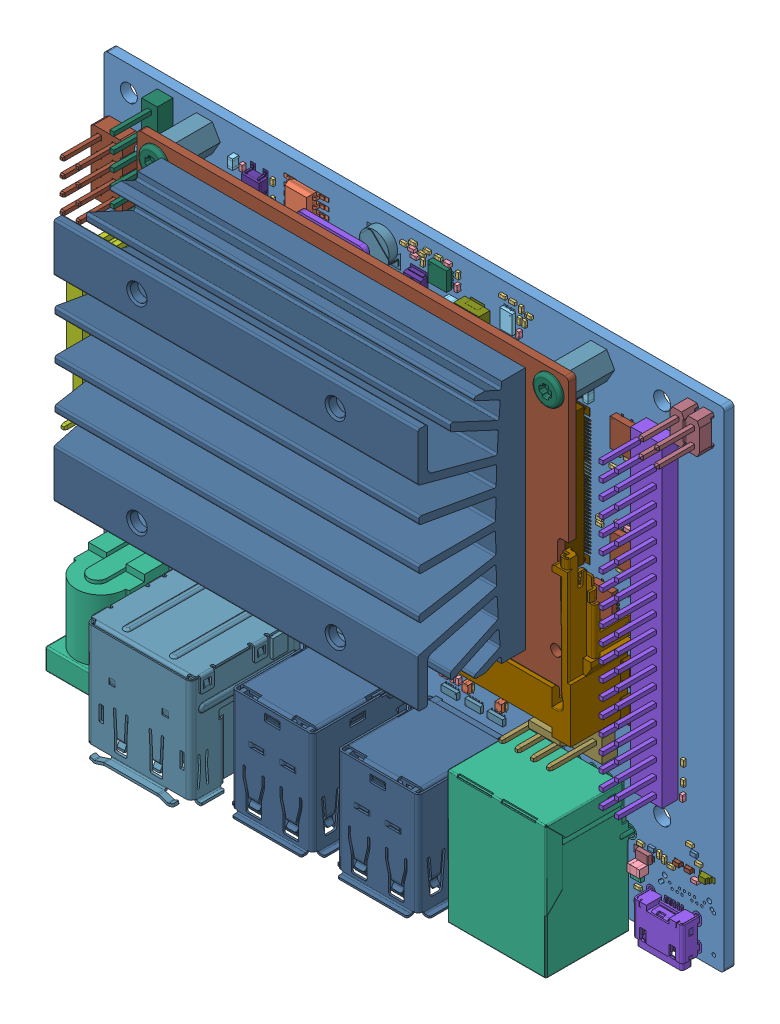
SolidWorks assembly Jetson nano_fixed.step, configuration Default. Lengths in mm.
Overall size (100 81.03 30.51).
400 component instances, 70 part files, 0 mates.
Components (placement in the parent):
- 142-13449-1000-A02_ASM.step-1: 142-13449-1000-A02_ASM.step [Default] at origin size (100 81.03 23.18)
  - 142-13449-1000-A02.step-1: 142-13449-1000-A02.step [Default] at origin size (100 79 1.57)
  - 315-1109-000_1.step-1: 315-1109-000_1.step [Default] at (5.6 4.9 1.575) x (-1 0 0) z (0 0 1) size (4.5 3.5 0.8)
  - 0402_H040.step-1: 0402_H040.step [Default] at (8 -0.825 1.575) size (1 0.5 0.4)
  - 0402_H060.step-1: 0402_H060.step [Default] at (1 5 1.575) x (0 -1 0) z (0 0 1) size (1 0.5 0.6)
  - 0402_H040.step-2: 0402_H040.step [Default] at (9.9 -0.3 1.575) size (1 0.5 0.4)
  - 0402_H040.step-3: 0402_H040.step [Default] at (8.296 51.194 1.575) x (-1 0 0) z (0 0 1) size (1 0.5 0.4)
  - 0402_H040.step-4: 0402_H040.step [Default] at (76.2 36.9 1.575) x (-1 0 0) z (0 0 1) size (1 0.5 0.4)
  - 0402_H040.step-5: 0402_H040.step [Default] at (37.8 2.87 1.575) x (0 -1 0) z (0 0 1) size (1 0.5 0.4)
  - 0402_H040.step-6: 0402_H040.step [Default] at (38.6 2.87 1.575) x (0 -1 0) z (0 0 1) size (1 0.5 0.4)
  - 0402_H060.step-2: 0402_H060.step [Default] at (14.2 7.7 1.575) x (0 -1 0) z (0 0 1) size (1 0.5 0.6)
  - 0402_H040.step-7: 0402_H040.step [Default] at (64 27.5 1.575) x (-1 0 0) z (0 0 1) size (1 0.5 0.4)
  - 0402_H060.step-3: 0402_H060.step [Default] at (18.6 43.15 1.575) x (-1 0 0) z (0 0 1) size (1 0.5 0.6)
  - 0402_H060.step-4: 0402_H060.step [Default] at (65.5 52.8 1.575) x (0 1 0) z (0 0 1) size (1 0.5 0.6)
  - 0402_H060.step-5: 0402_H060.step [Default] at (64 28.4 1.575) x (-1 0 0) z (0 0 1) size (1 0.5 0.6)
  - 0402_H040.step-8: 0402_H040.step [Default] at (60.95 25.85 1.575) size (1 0.5 0.4)
  - 0402_H060.step-6: 0402_H060.step [Default] at (17.3 7.7 1.575) x (0 -1 0) z (0 0 1) size (1 0.5 0.6)
  - 0402_H060.step-7: 0402_H060.step [Default] at (18.6 7.7 1.575) x (0 -1 0) z (0 0 1) size (1 0.5 0.6)
  - 0402_H060.step-8: 0402_H060.step [Default] at (12.9 7.7 1.575) x (0 -1 0) z (0 0 1) size (1 0.5 0.6)
  - 0402_H060.step-9: 0402_H060.step [Default] at (80.9 37.7 1.575) x (-1 0 0) z (0 0 1) size (1 0.5 0.6)
  - 0402_H040.step-9: 0402_H040.step [Default] at (79.5 31.3 1.575) size (1 0.5 0.4)
  - 0402_H040.step-10: 0402_H040.step [Default] at (81 31.3 1.575) x (-1 0 0) z (0 0 1) size (1 0.5 0.4)
  - 0402_H060.step-10: 0402_H060.step [Default] at (79.3 37.7 1.575) size (1 0.5 0.6)
  - 0402_H060.step-11: 0402_H060.step [Default] at (74.8 4.05 1.575) x (-1 0 0) z (0 0 1) size (1 0.5 0.6)
  - 0402_H040.step-11: 0402_H040.step [Default] at (65.675 6.15 1.575) x (0 -1 0) z (0 0 1) size (1 0.5 0.4)
  - 0402_H060.step-12: 0402_H060.step [Default] at (67.7 6.85 1.575) x (0 1 0) z (0 0 1) size (1 0.5 0.6)
  - 0402_H040.step-12: 0402_H040.step [Default] at (64.475 5.8 1.575) x (-1 0 0) z (0 0 1) size (1 0.5 0.4)
  - 0402_H040.step-13: 0402_H040.step [Default] at (67.725 5.325 1.575) x (0 1 0) z (0 0 1) size (1 0.5 0.4)
  - 0402_H060.step-13: 0402_H060.step [Default] at (46.1 59.45 1.575) size (1 0.5 0.6)
  - 0402_H040.step-14: 0402_H040.step [Default] at (44.65 59.45 1.575) size (1 0.5 0.4)
  - 0402_H040.step-15: 0402_H040.step [Default] at (46.1 60.25 1.575) size (1 0.5 0.4)
  - 0402_H060.step-14: 0402_H060.step [Default] at (53.35 57.7 1.575) x (0 -1 0) z (0 0 1) size (1 0.5 0.6)
  - 0402_H040.step-16: 0402_H040.step [Default] at (47.6 59.45 1.575) size (1 0.5 0.4)
  - 0402_H040.step-17: 0402_H040.step [Default] at (48.4 60.25 1.575) size (1 0.5 0.4)
  - 0402_H040.step-18: 0402_H040.step [Default] at (47.7 58.325 1.575) x (0 1 0) z (0 0 1) size (1 0.5 0.4)
  - 0402_H060.step-15: 0402_H060.step [Default] at (46.5 58.65 1.575) x (-1 0 0) z (0 0 1) size (1 0.5 0.6)
  - 0402_H060.step-16: 0402_H060.step [Default] at (51.8 60.25 1.575) size (1 0.5 0.6)
  - 0402_H040.step-19: 0402_H040.step [Default] at (53.35 59.4 1.575) x (0 -1 0) z (0 0 1) size (1 0.5 0.4)
  - 0402_H040.step-20: 0402_H040.step [Default] at (50.2 60.25 1.575) x (-1 0 0) z (0 0 1) size (1 0.5 0.4)
  - 0402_H060.step-17: 0402_H060.step [Default] at (18.6 43.95 1.575) x (-1 0 0) z (0 0 1) size (1 0.5 0.6)
  - 0402_H060.step-18: 0402_H060.step [Default] at (52.75 2.9 1.575) x (0 -1 0) z (0 0 1) size (1 0.5 0.6)
  - 0402_H060.step-19: 0402_H060.step [Default] at (22.35 47.4 1.575) x (-1 0 0) z (0 0 1) size (1 0.5 0.6)
  - 0402_H060.step-20: 0402_H060.step [Default] at (20.55 47.4 1.575) x (-1 0 0) z (0 0 1) size (1 0.5 0.6)
  - 0402_H060.step-21: 0402_H060.step [Default] at (21.95 34.55 1.575) x (0 -1 0) z (0 0 1) size (1 0.5 0.6)
  - 0402_H060.step-22: 0402_H060.step [Default] at (21.05 34.55 1.575) x (0 -1 0) z (0 0 1) size (1 0.5 0.6)
  - 0402_H060.step-23: 0402_H060.step [Default] at (53.55 2.9 1.575) x (0 -1 0) z (0 0 1) size (1 0.5 0.6)
  - 0402_H060.step-24: 0402_H060.step [Default] at (25.4 54 1.575) x (-1 0 0) z (0 0 1) size (1 0.5 0.6)
  - 0402_H060.step-25: 0402_H060.step [Default] at (24 34.58 1.575) x (0 -1 0) z (0 0 1) size (1 0.5 0.6)
  - 0402_H040.step-21: 0402_H040.step [Default] at (55.6 2.95 1.575) x (0 -1 0) z (0 0 1) size (1 0.5 0.4)
  - 0402_H040.step-22: 0402_H040.step [Default] at (20.13 34.53 1.575) x (0 1 0) z (0 0 1) size (1 0.5 0.4)
  - 0402_H060.step-26: 0402_H060.step [Default] at (18.4 35.15 1.575) x (0 1 0) z (0 0 1) size (1 0.5 0.6)
  - 0402_H060.step-27: 0402_H060.step [Default] at (18.4 36.75 1.575) x (0 1 0) z (0 0 1) size (1 0.5 0.6)
  - 0402_H040.step-23: 0402_H040.step [Default] at (39.6 2.87 1.575) x (0 -1 0) z (0 0 1) size (1 0.5 0.4)
  - 0402_H040.step-24: 0402_H040.step [Default] at (40.4 2.87 1.575) x (0 -1 0) z (0 0 1) size (1 0.5 0.4)
  - 0402_H040.step-25: 0402_H040.step [Default] at (60.95 2.95 1.575) x (0 -1 0) z (0 0 1) size (1 0.5 0.4)
  - 0402_H040.step-26: 0402_H040.step [Default] at (60.15 2.95 1.575) x (0 -1 0) z (0 0 1) size (1 0.5 0.4)
  - 0402_H040.step-27: 0402_H040.step [Default] at (54.8 2.95 1.575) x (0 -1 0) z (0 0 1) size (1 0.5 0.4)
  - 0402_H040.step-28: 0402_H040.step [Default] at (31.6 54 1.575) size (1 0.5 0.4)
  - 0402_H040.step-29: 0402_H040.step [Default] at (27.4 54 1.575) size (1 0.5 0.4)
  - 0402_H040.step-30: 0402_H040.step [Default] at (29.6 54 1.575) x (-1 0 0) z (0 0 1) size (1 0.5 0.4)
  - 0402_H040.step-31: 0402_H040.step [Default] at (63.775 -14.475 1.575) size (1 0.5 0.4)
  - 0402_H040.step-32: 0402_H040.step [Default] at (63.775 -15.275 1.575) size (1 0.5 0.4)
  - 0402_H040.step-33: 0402_H040.step [Default] at (8.025 41.475 1.575) x (-1 0 0) z (0 0 1) size (1 0.5 0.4)
  - 0402_H060.step-28: 0402_H060.step [Default] at (63.95 1.25 1.575) x (0 1 0) z (0 0 1) size (1 0.5 0.6)
  - 0402_H060.step-29: 0402_H060.step [Default] at (2.95 54.05 1.575) x (0 1 0) z (0 0 1) size (1 0.5 0.6)
  - 0402_H040.step-34: 0402_H040.step [Default] at (92.2 -3.45 1.575) x (-1 0 0) z (0 0 1) size (1 0.5 0.4)
  - 0402_H060.step-30: 0402_H060.step [Default] at (32.85 7.7 1.575) x (0 -1 0) z (0 0 1) size (1 0.5 0.6)
  - 0402_H060.step-31: 0402_H060.step [Default] at (27.25 7.7 1.575) x (0 -1 0) z (0 0 1) size (1 0.5 0.6)
  - 0402_H060.step-32: 0402_H060.step [Default] at (31.25 7.7 1.575) x (0 -1 0) z (0 0 1) size (1 0.5 0.6)
  - 0402_H060.step-33: 0402_H060.step [Default] at (28.85 7.7 1.575) x (0 -1 0) z (0 0 1) size (1 0.5 0.6)
  - 0402_H060.step-34: 0402_H060.step [Default] at (32.05 7.7 1.575) x (0 -1 0) z (0 0 1) size (1 0.5 0.6)
  - 0402_H060.step-35: 0402_H060.step [Default] at (28.05 7.7 1.575) x (0 -1 0) z (0 0 1) size (1 0.5 0.6)
  - 0402_H060.step-36: 0402_H060.step [Default] at (30.45 7.7 1.575) x (0 -1 0) z (0 0 1) size (1 0.5 0.6)
  - 0402_H060.step-37: 0402_H060.step [Default] at (29.65 7.7 1.575) x (0 -1 0) z (0 0 1) size (1 0.5 0.6)
  - 0402_H060.step-38: 0402_H060.step [Default] at (24.65 6.41 1.575) x (0 -1 0) z (0 0 1) size (1 0.5 0.6)
  - 0402_H060.step-39: 0402_H060.step [Default] at (25.85 6.41 1.575) x (0 -1 0) z (0 0 1) size (1 0.5 0.6)
  - 0402_H060.step-40: 0402_H060.step [Default] at (4.2 36.5 1.575) x (0 1 0) z (0 0 1) size (1 0.5 0.6)
  - 0402_H060.step-41: 0402_H060.step [Default] at (89.7 4.7 1.575) x (0 -1 0) z (0 0 1) size (1 0.5 0.6)
  - 0402_H060.step-42: 0402_H060.step [Default] at (82.5 3.8 1.575) x (0 -1 0) z (0 0 1) size (1 0.5 0.6)
  - 0402_H060.step-43: 0402_H060.step [Default] at (12.65 49.7 1.575) size (1 0.5 0.6)
  - 0402_H060.step-44: 0402_H060.step [Default] at (11.2 50.15 1.575) x (0 -1 0) z (0 0 1) size (1 0.5 0.6)
  - 0402_H060.step-45: 0402_H060.step [Default] at (26.5 34.55 1.575) x (0 -1 0) z (0 0 1) size (1 0.5 0.6)
  - 0402_H060.step-46: 0402_H060.step [Default] at (29.9 34.5 1.575) x (0 -1 0) z (0 0 1) size (1 0.5 0.6)
  - 0402_H060.step-47: 0402_H060.step [Default] at (31.7 40.15 1.575) x (0 1 0) z (0 0 1) size (1 0.5 0.6)
  - 0402_H060.step-48: 0402_H060.step [Default] at (31.15 42.5 1.575) x (0 1 0) z (0 0 1) size (1 0.5 0.6)
  - 0402_H060.step-49: 0402_H060.step [Default] at (19.2 47.05 1.575) x (0 1 0) z (0 0 1) size (1 0.5 0.6)
  - 0402_H060.step-50: 0402_H060.step [Default] at (17.95 42 1.575) x (0 -1 0) z (0 0 1) size (1 0.5 0.6)
  - 0402_H060.step-51: 0402_H060.step [Default] at (27.3 48.25 1.575) x (0 1 0) z (0 0 1) size (1 0.5 0.6)
  - 0402_H060.step-52: 0402_H060.step [Default] at (31.7 37.85 1.575) x (0 -1 0) z (0 0 1) size (1 0.5 0.6)
  - 0402_H060.step-53: 0402_H060.step [Default] at (29.6 48.35 1.575) x (0 1 0) z (0 0 1) size (1 0.5 0.6)
  - 0402_H060.step-54: 0402_H060.step [Default] at (18.8 38.75 1.575) x (-1 0 0) z (0 0 1) size (1 0.5 0.6)
  - 0402_H060.step-55: 0402_H060.step [Default] at (18.7 57.2 1.575) x (0 -1 0) z (0 0 1) size (1 0.5 0.6)
  - 0402_H060.step-56: 0402_H060.step [Default] at (34.1 2.9 1.575) x (0 -1 0) z (0 0 1) size (1 0.5 0.6)
  - 0402_H060.step-57: 0402_H060.step [Default] at (35.8 2.9 1.575) x (0 -1 0) z (0 0 1) size (1 0.5 0.6)
  - 0402_H060.step-58: 0402_H060.step [Default] at (34.9 2.9 1.575) x (0 -1 0) z (0 0 1) size (1 0.5 0.6)
  - 0402_H060.step-59: 0402_H060.step [Default] at (36.6 2.9 1.575) x (0 -1 0) z (0 0 1) size (1 0.5 0.6)
  - 0402_H060.step-60: 0402_H060.step [Default] at (11.325 44.725 1.575) size (1 0.5 0.6)
  - 0402_H060.step-61: 0402_H060.step [Default] at (50.95 2.9 1.575) x (0 -1 0) z (0 0 1) size (1 0.5 0.6)
  - 0402_H060.step-62: 0402_H060.step [Default] at (51.75 2.9 1.575) x (0 -1 0) z (0 0 1) size (1 0.5 0.6)
  - 0402_H060.step-63: 0402_H060.step [Default] at (11.55 39.7 1.575) size (1 0.5 0.6)
  - 0402_H060.step-64: 0402_H060.step [Default] at (9.5 -8.5 1.575) x (-1 0 0) z (0 0 1) size (1 0.5 0.6)
  - 0402_H060.step-65: 0402_H060.step [Default] at (61.35 38.05 1.575) x (0 -1 0) z (0 0 1) size (1 0.5 0.6)
  - 0402_H060.step-66: 0402_H060.step [Default] at (60.55 38.05 1.575) x (0 -1 0) z (0 0 1) size (1 0.5 0.6)
  - 0402_H060.step-67: 0402_H060.step [Default] at (29.3 25.65 1.575) x (0 -1 0) z (0 0 1) size (1 0.5 0.6)
  - 0402_H060.step-68: 0402_H060.step [Default] at (63.3 56.2 1.575) x (0 1 0) z (0 0 1) size (1 0.5 0.6)
  - 0402_H060.step-69: 0402_H060.step [Default] at (20.5 54.2 1.575) size (1 0.5 0.6)
  - 0402_H060.step-70: 0402_H060.step [Default] at (60.1 32.15 1.575) x (0 1 0) z (0 0 1) size (1 0.5 0.6)
  - 0402_H060.step-71: 0402_H060.step [Default] at (60.9 32.15 1.575) x (0 1 0) z (0 0 1) size (1 0.5 0.6)
  - 0402_H060.step-72: 0402_H060.step [Default] at (18.6 44.85 1.575) size (1 0.5 0.6)
  - 0402_H060.step-73: 0402_H060.step [Default] at (18.6 45.65 1.575) size (1 0.5 0.6)
  - 0402_H060.step-74: 0402_H060.step [Default] at (18.1 27.25 1.575) size (1 0.5 0.6)
  - 0402_H060.step-75: 0402_H060.step [Default] at (15.1 7.7 1.575) x (0 -1 0) z (0 0 1) size (1 0.5 0.6)
  - 0402_H060.step-76: 0402_H060.step [Default] at (16.4 7.7 1.575) x (0 -1 0) z (0 0 1) size (1 0.5 0.6)
  - 0402_H060.step-77: 0402_H060.step [Default] at (20.8 7.7 1.575) x (0 -1 0) z (0 0 1) size (1 0.5 0.6)
  - 0402_H060.step-78: 0402_H060.step [Default] at (19.5 7.7 1.575) x (0 -1 0) z (0 0 1) size (1 0.5 0.6)
  - 0402_H060.step-79: 0402_H060.step [Default] at (21.9 2.8 1.575) size (1 0.5 0.6)
  - 0402_H060.step-80: 0402_H060.step [Default] at (12.75 29 1.575) size (1 0.5 0.6)
  - 0402_H060.step-81: 0402_H060.step [Default] at (10.225 5.1 1.575) size (1 0.5 0.6)
  - 0402_H060.step-82: 0402_H060.step [Default] at (22.8 27.65 1.575) x (0 1 0) z (0 0 1) size (1 0.5 0.6)
  - 0402_H060.step-83: 0402_H060.step [Default] at (18.85 25.15 1.575) x (0 -1 0) z (0 0 1) size (1 0.5 0.6)
  - 0402_H060.step-84: 0402_H060.step [Default] at (17.95 40.1 1.575) x (0 1 0) z (0 0 1) size (1 0.5 0.6)
  - 0402_H040.step-35: 0402_H040.step [Default] at (20.8 6.2 1.575) x (0 1 0) z (0 0 1) size (1 0.5 0.4)
  - 0402_H040.step-36: 0402_H040.step [Default] at (76 22.7 1.575) size (1 0.5 0.4)
  - 0402_H040.step-37: 0402_H040.step [Default] at (23.7 26.85 1.575) x (0 1 0) z (0 0 1) size (1 0.5 0.4)
  - 0402_H040.step-38: 0402_H040.step [Default] at (18 25.15 1.575) x (0 1 0) z (0 0 1) size (1 0.5 0.4)
  - 0402_H040.step-39: 0402_H040.step [Default] at (17.3 28.25 1.575) x (-1 0 0) z (0 0 1) size (1 0.5 0.4)
  - 0402_H040.step-40: 0402_H040.step [Default] at (13.15 4.2 1.575) x (0 -1 0) z (0 0 1) size (1 0.5 0.4)
  - 0402_H040.step-41: 0402_H040.step [Default] at (17.2 30.15 1.575) x (0 -1 0) z (0 0 1) size (1 0.5 0.4)
  - 0402_H040.step-42: 0402_H040.step [Default] at (14.2 6.2 1.575) x (0 1 0) z (0 0 1) size (1 0.5 0.4)
  - 0402_H040.step-43: 0402_H040.step [Default] at (12.9 6.2 1.575) x (0 1 0) z (0 0 1) size (1 0.5 0.4)
  - 0402_H040.step-44: 0402_H040.step [Default] at (15.1 6.2 1.575) x (0 1 0) z (0 0 1) size (1 0.5 0.4)
  - 0402_H040.step-45: 0402_H040.step [Default] at (16.4 6.2 1.575) x (0 1 0) z (0 0 1) size (1 0.5 0.4)
  - 0402_H040.step-46: 0402_H040.step [Default] at (19.5 6.2 1.575) x (0 1 0) z (0 0 1) size (1 0.5 0.4)
  - 0402_H040.step-47: 0402_H040.step [Default] at (17.3 6.2 1.575) x (0 1 0) z (0 0 1) size (1 0.5 0.4)
  - 0402_H040.step-48: 0402_H040.step [Default] at (18.6 6.2 1.575) x (0 1 0) z (0 0 1) size (1 0.5 0.4)
  - 0402_H040.step-49: 0402_H040.step [Default] at (24.2 24.55 1.575) x (0 1 0) z (0 0 1) size (1 0.5 0.4)
  - 0402_H040.step-50: 0402_H040.step [Default] at (23.5 54.9 1.575) x (0 1 0) z (0 0 1) size (1 0.5 0.4)
  - 0402_H040.step-51: 0402_H040.step [Default] at (13.2 39.75 1.575) x (-1 0 0) z (0 0 1) size (1 0.5 0.4)
  - 0402_H040.step-52: 0402_H040.step [Default] at (80.7 47.4 1.575) x (-1 0 0) z (0 0 1) size (1 0.5 0.4)
  - 0402_H040.step-53: 0402_H040.step [Default] at (77.5 22.7 1.575) x (-1 0 0) z (0 0 1) size (1 0.5 0.4)
  - 0402_H040.step-54: 0402_H040.step [Default] at (9.25 -12.75 1.575) x (-1 0 0) z (0 0 1) size (1 0.5 0.4)
  - 0402_H040.step-55: 0402_H040.step [Default] at (9.25 -11.95 1.575) x (-1 0 0) z (0 0 1) size (1 0.5 0.4)
  - 0402_H040.step-56: 0402_H040.step [Default] at (64.475 6.7 1.575) size (1 0.5 0.4)
  - 0402_H040.step-57: 0402_H040.step [Default] at (29.3 24 1.575) x (0 1 0) z (0 0 1) size (1 0.5 0.4)
  - 0402_H040.step-58: 0402_H040.step [Default] at (64.2 32.5 1.575) x (0 1 0) z (0 0 1) size (1 0.5 0.4)
  - 0402_H040.step-59: 0402_H040.step [Default] at (64.15 47.45 1.575) x (0 -1 0) z (0 0 1) size (1 0.5 0.4)
  - 0402_H040.step-60: 0402_H040.step [Default] at (64.2 31 1.575) x (0 -1 0) z (0 0 1) size (1 0.5 0.4)
  - 0402_H040.step-61: 0402_H040.step [Default] at (76.2 36.1 1.575) x (-1 0 0) z (0 0 1) size (1 0.5 0.4)
  - 0402_H040.step-62: 0402_H040.step [Default] at (78.4 45.15 1.575) size (1 0.5 0.4)
  - 0402_H040.step-63: 0402_H040.step [Default] at (81.7 38.6 1.575) size (1 0.5 0.4)
  - 0402_H040.step-64: 0402_H040.step [Default] at (81.7 39.4 1.575) size (1 0.5 0.4)
  - 0402_H040.step-65: 0402_H040.step [Default] at (59.35 51.825 1.575) size (1 0.5 0.4)
  - 0402_H040.step-66: 0402_H040.step [Default] at (60.825 51.825 1.575) x (-1 0 0) z (0 0 1) size (1 0.5 0.4)
  - 0402_H040.step-67: 0402_H040.step [Default] at (89.7 9.5 1.575) x (0 1 0) z (0 0 1) size (1 0.5 0.4)
  - 0402_H040.step-68: 0402_H040.step [Default] at (89.7 6.7 1.575) x (0 1 0) z (0 0 1) size (1 0.5 0.4)
  - 0402_H040.step-69: 0402_H040.step [Default] at (3.9 34.2 1.575) x (0 -1 0) z (0 0 1) size (1 0.5 0.4)
  - 0402_H040.step-70: 0402_H040.step [Default] at (5.1 35 1.575) x (0 1 0) z (0 0 1) size (1 0.5 0.4)
  - 0402_H040.step-71: 0402_H040.step [Default] at (32.85 5.81 1.575) x (0 -1 0) z (0 0 1) size (1 0.5 0.4)
  - 0402_H040.step-72: 0402_H040.step [Default] at (32.05 5.81 1.575) x (0 -1 0) z (0 0 1) size (1 0.5 0.4)
  - 0402_H040.step-73: 0402_H040.step [Default] at (27.25 5.81 1.575) x (0 -1 0) z (0 0 1) size (1 0.5 0.4)
  - 0402_H040.step-74: 0402_H040.step [Default] at (28.05 5.81 1.575) x (0 -1 0) z (0 0 1) size (1 0.5 0.4)
  - 0402_H040.step-75: 0402_H040.step [Default] at (31.25 5.81 1.575) x (0 -1 0) z (0 0 1) size (1 0.5 0.4)
  - 0402_H040.step-76: 0402_H040.step [Default] at (30.45 5.81 1.575) x (0 -1 0) z (0 0 1) size (1 0.5 0.4)
  - 0402_H040.step-77: 0402_H040.step [Default] at (28.85 5.81 1.575) x (0 -1 0) z (0 0 1) size (1 0.5 0.4)
  - 0402_H040.step-78: 0402_H040.step [Default] at (29.65 5.81 1.575) x (0 -1 0) z (0 0 1) size (1 0.5 0.4)
  - 0402_H040.step-79: 0402_H040.step [Default] at (13.5 52.9 1.575) x (-1 0 0) z (0 0 1) size (1 0.5 0.4)
  - 0402_H040.step-80: 0402_H040.step [Default] at (22.35 4 1.575) x (0 -1 0) z (0 0 1) size (1 0.5 0.4)
  - 0402_H040.step-81: 0402_H040.step [Default] at (21.55 4 1.575) x (0 1 0) z (0 0 1) size (1 0.5 0.4)
  - 0402_H040.step-82: 0402_H040.step [Default] at (25.85 4.9 1.575) x (0 -1 0) z (0 0 1) size (1 0.5 0.4)
  - 0402_H040.step-83: 0402_H040.step [Default] at (11.8 52.9 1.575) size (1 0.5 0.4)
  - 0402_H040.step-84: 0402_H040.step [Default] at (9.432 51.594 1.575) x (0 -1 0) z (0 0 1) size (1 0.5 0.4)
  - 0402_H040.step-85: 0402_H040.step [Default] at (8.975 50.3 1.575) size (1 0.5 0.4)
  - 0402_H040.step-86: 0402_H040.step [Default] at (82.8 -5.3 1.575) x (-1 0 0) z (0 0 1) size (1 0.5 0.4)
  - 0402_H040.step-87: 0402_H040.step [Default] at (82.4 -11.6 1.575) x (-1 0 0) z (0 0 1) size (1 0.5 0.4)
  - 0402_H040.step-88: 0402_H040.step [Default] at (22.8 26.05 1.575) x (0 1 0) z (0 0 1) size (1 0.5 0.4)
  - 0402_H040.step-89: 0402_H040.step [Default] at (20.8 28.25 1.575) size (1 0.5 0.4)
  - 0402_H040.step-90: 0402_H040.step [Default] at (20.8 24.65 1.575) x (-1 0 0) z (0 0 1) size (1 0.5 0.4)
  - 0402_H040.step-91: 0402_H040.step [Default] at (18.1 26.45 1.575) size (1 0.5 0.4)
  - 0402_H040.step-92: 0402_H040.step [Default] at (24.65 8.41 1.575) x (0 1 0) z (0 0 1) size (1 0.5 0.4)
  - 0402_H040.step-93: 0402_H040.step [Default] at (25.85 8.41 1.575) x (0 1 0) z (0 0 1) size (1 0.5 0.4)
  - 0402_H040.step-94: 0402_H040.step [Default] at (3.8 54.4 1.575) x (0 -1 0) z (0 0 1) size (1 0.5 0.4)
  - 0402_H040.step-95: 0402_H040.step [Default] at (2.45 44.45 1.575) x (0 -1 0) z (0 0 1) size (1 0.5 0.4)
  - 0402_H040.step-96: 0402_H040.step [Default] at (24.65 4.9 1.575) x (0 1 0) z (0 0 1) size (1 0.5 0.4)
  - 0402_H040.step-97: 0402_H040.step [Default] at (22.15 7.6 1.575) x (-1 0 0) z (0 0 1) size (1 0.5 0.4)
  - 0402_H040.step-98: 0402_H040.step [Default] at (79.2 47.4 1.575) size (1 0.5 0.4)
  - 0402_H040.step-99: 0402_H040.step [Default] at (19 28.25 1.575) size (1 0.5 0.4)
  - 0402_H040.step-100: 0402_H040.step [Default] at (9.65 9.7 1.575) x (0 -1 0) z (0 0 1) size (1 0.5 0.4)
  - 0402_H040.step-101: 0402_H040.step [Default] at (28.35 34.45 1.575) x (0 1 0) z (0 0 1) size (1 0.5 0.4)
  - 0402_H040.step-102: 0402_H040.step [Default] at (25.2 34.55 1.575) x (0 1 0) z (0 0 1) size (1 0.5 0.4)
  - 0402_H040.step-103: 0402_H040.step [Default] at (10.625 6.35 1.575) x (0 -1 0) z (0 0 1) size (1 0.5 0.4)
  - 0402_H040.step-104: 0402_H040.step [Default] at (9.825 6.35 1.575) x (0 1 0) z (0 0 1) size (1 0.5 0.4)
  - 0402_H040.step-105: 0402_H040.step [Default] at (4.775 42.975 1.575) x (0 1 0) z (0 0 1) size (1 0.5 0.4)
  - 0402_H040.step-106: 0402_H040.step [Default] at (19.8 32.9 1.575) x (-1 0 0) z (0 0 1) size (1 0.5 0.4)
  - 0402_H040.step-107: 0402_H040.step [Default] at (22.35 24.65 1.575) x (-1 0 0) z (0 0 1) size (1 0.5 0.4)
  - 0402_H040.step-108: 0402_H040.step [Default] at (62.4 54.7 1.575) size (1 0.5 0.4)
  - 0402_H040.step-109: 0402_H040.step [Default] at (62.2 60.05 1.575) x (-1 0 0) z (0 0 1) size (1 0.5 0.4)
  - 0402_H040.step-110: 0402_H040.step [Default] at (23.5 57.5 1.575) x (0 1 0) z (0 0 1) size (1 0.5 0.4)
  - 0402_H040.step-111: 0402_H040.step [Default] at (12.8 44.725 1.575) size (1 0.5 0.4)
  - 0402_H040.step-112: 0402_H040.step [Default] at (21.8 31.45 1.575) x (0 1 0) z (0 0 1) size (1 0.5 0.4)
  - 0402_H040.step-113: 0402_H040.step [Default] at (19.25 34.55 1.575) x (0 1 0) z (0 0 1) size (1 0.5 0.4)
  - 0402_H040.step-114: 0402_H040.step [Default] at (0.95 41.55 1.575) size (1 0.5 0.4)
  - 0402_H040.step-115: 0402_H040.step [Default] at (64.1 58 1.575) x (0 1 0) z (0 0 1) size (1 0.5 0.4)
  - 0402_H040.step-116: 0402_H040.step [Default] at (63.3 58 1.575) x (0 -1 0) z (0 0 1) size (1 0.5 0.4)
  - 0402_H040.step-117: 0402_H040.step [Default] at (63.55 59.7 1.575) x (0 -1 0) z (0 0 1) size (1 0.5 0.4)
  - 0402_H060.step-85: 0402_H060.step [Default] at (71.175 4 1.575) x (-1 0 0) z (0 0 1) size (1 0.5 0.6)
  - 0402_H040.step-118: 0402_H040.step [Default] at (86.6 -5.6 1.575) x (0 1 0) z (0 0 1) size (1 0.5 0.4)
  - 0402_H040.step-119: 0402_H040.step [Default] at (85.8 -5.3 1.575) x (0 1 0) z (0 0 1) size (1 0.5 0.4)
  - 0402_H040.step-120: 0402_H040.step [Default] at (10.25 51.6 1.575) x (0 1 0) z (0 0 1) size (1 0.5 0.4)
  - 0402_H040.step-121: 0402_H040.step [Default] at (80.5 28.55 1.575) size (1 0.5 0.4)
  - 0402_H040.step-122: 0402_H040.step [Default] at (13.95 4.2 1.575) x (0 -1 0) z (0 0 1) size (1 0.5 0.4)
  - 0402_H040.step-123: 0402_H040.step [Default] at (15.35 4.2 1.575) x (0 -1 0) z (0 0 1) size (1 0.5 0.4)
  - 0402_H040.step-124: 0402_H040.step [Default] at (16.15 4.2 1.575) x (0 -1 0) z (0 0 1) size (1 0.5 0.4)
  - 0402_H040.step-125: 0402_H040.step [Default] at (20.55 4.2 1.575) x (0 -1 0) z (0 0 1) size (1 0.5 0.4)
  - 0402_H040.step-126: 0402_H040.step [Default] at (19.75 4.2 1.575) x (0 -1 0) z (0 0 1) size (1 0.5 0.4)
  - 0402_H040.step-127: 0402_H040.step [Default] at (17.6 4.2 1.575) x (0 -1 0) z (0 0 1) size (1 0.5 0.4)
  - 0402_H040.step-128: 0402_H040.step [Default] at (18.4 4.2 1.575) x (0 -1 0) z (0 0 1) size (1 0.5 0.4)
  - 0402_H060.step-86: 0402_H060.step [Default] at (64.25 -13.325 1.575) x (0 -1 0) z (0 0 1) size (1 0.5 0.6)
  - 0402_H060.step-87: 0402_H060.step [Default] at (64.225 -11.825 1.575) x (0 1 0) z (0 0 1) size (1 0.5 0.6)
  - 0402_H040.step-129: 0402_H040.step [Default] at (63.8 -6.85 1.575) x (0 1 0) z (0 0 1) size (1 0.5 0.4)
  - 0402_H040.step-130: 0402_H040.step [Default] at (81.7 41.95 1.575) size (1 0.5 0.4)
  - 0402_H040.step-131: 0402_H040.step [Default] at (87.75 -6 1.575) x (-1 0 0) z (0 0 1) size (1 0.5 0.4)
  - 0402_H040.step-132: 0402_H040.step [Default] at (82.4 -13.6 1.575) x (-1 0 0) z (0 0 1) size (1 0.5 0.4)
  - 0402_H060.step-88: 0402_H060.step [Default] at (91.75 -5.95 1.575) size (1 0.5 0.6)
  - 0402_H040.step-133: 0402_H040.step [Default] at (3.65 49.25 1.575) x (0 -1 0) z (0 0 1) size (1 0.5 0.4)
  - 0402_H040.step-134: 0402_H040.step [Default] at (2.45 49.25 1.575) x (0 1 0) z (0 0 1) size (1 0.5 0.4)
  - 0402_H040.step-135: 0402_H040.step [Default] at (90.75 -1.45 1.575) x (-1 0 0) z (0 0 1) size (1 0.5 0.4)
  - 0402_H040.step-136: 0402_H040.step [Default] at (8.45 39.55 1.575) x (0 -1 0) z (0 0 1) size (1 0.5 0.4)
  - 0402_H060.step-89: 0402_H060.step [Default] at (8.85 -5.25 1.575) x (-1 0 0) z (0 0 1) size (1 0.5 0.6)
  - 0402_H040.step-137: 0402_H040.step [Default] at (18.6 32.55 1.575) x (0 1 0) z (0 0 1) size (1 0.5 0.4)
  - 0402_H060.step-90: 0402_H060.step [Default] at (4.5 44.45 1.575) x (0 1 0) z (0 0 1) size (1 0.5 0.6)
  - 0402_H040.step-138: 0402_H040.step [Default] at (8.35 2.75 1.575) size (1 0.5 0.4)
  - 0402_H040.step-139: 0402_H040.step [Default] at (9.4 1.95 1.575) size (1 0.5 0.4)
  - 0402_H040.step-140: 0402_H040.step [Default] at (8.2 1.55 1.575) x (0 1 0) z (0 0 1) size (1 0.5 0.4)
  - 0402_H060.step-91: 0402_H060.step [Default] at (8.5 3.875 1.575) x (0 -1 0) z (0 0 1) size (1 0.5 0.6)
  - 0402_H060.step-92: 0402_H060.step [Default] at (-0.8 41.5 1.575) x (-1 0 0) z (0 0 1) size (1 0.5 0.6)
  - 0402_H040.step-141: 0402_H040.step [Default] at (-1.35 7.75 1.575) size (1 0.5 0.4)
  - 0402_H040.step-142: 0402_H040.step [Default] at (8 0.425 1.575) size (1 0.5 0.4)
  - 0402_H040.step-143: 0402_H040.step [Default] at (67.9 4.025 1.575) x (-1 0 0) z (0 0 1) size (1 0.5 0.4)
  - 0402_H040.step-144: 0402_H040.step [Default] at (60.6 60.05 1.575) x (-1 0 0) z (0 0 1) size (1 0.5 0.4)
  - 0402_H040.step-145: 0402_H040.step [Default] at (72.85 4 1.575) x (-1 0 0) z (0 0 1) size (1 0.5 0.4)
  - 0402_H040.step-146: 0402_H040.step [Default] at (64.8 59.35 1.575) size (1 0.5 0.4)
  - 0402_H040.step-147: 0402_H040.step [Default] at (7.2 7.3 1.575) size (1 0.5 0.4)
  - 0402_H040.step-148: 0402_H040.step [Default] at (8.5 5.35 1.575) x (0 1 0) z (0 0 1) size (1 0.5 0.4)
  - 0402_H040.step-149: 0402_H040.step [Default] at (8.475 7.075 1.575) x (0 1 0) z (0 0 1) size (1 0.5 0.4)
  - VIRTUAL_SHORT.step-1: VIRTUAL_SHORT.step [Default] at (23.5 32.9 1.575) x (0 1 0) z (0 0 1) size (0.25 0.25 1)
  - VIRTUAL_SHORT.step-2: VIRTUAL_SHORT.step [Default] at (26.85 32.85 1.575) x (0 1 0) z (0 0 1) size (0.25 0.25 1)
  - VIRTUAL_SHORT.step-3: VIRTUAL_SHORT.step [Default] at (30.6 33.8 1.575) x (0 1 0) z (0 0 1) size (0.25 0.25 1)
  - VIRTUAL_SHORT.step-4: VIRTUAL_SHORT.step [Default] at (32.65 39.75 1.575) x (-1 0 0) z (0 0 1) size (0.25 0.25 1)
  - VIRTUAL_SHORT.step-5: VIRTUAL_SHORT.step [Default] at (31.85 42.1 1.575) x (-1 0 0) z (0 0 1) size (0.25 0.25 1)
  - VIRTUAL_SHORT.step-6: VIRTUAL_SHORT.step [Default] at (17.35 42.4 1.575) size (0.25 0.25 1)
  - VIRTUAL_SHORT.step-7: VIRTUAL_SHORT.step [Default] at (18.6 46.6 1.575) size (0.25 0.25 1)
  - VIRTUAL_SHORT.step-8: VIRTUAL_SHORT.step [Default] at (20.9 32.9 1.575) x (0 1 0) z (0 0 1) size (0.25 0.25 1)
  - VIRTUAL_SHORT.step-9: VIRTUAL_SHORT.step [Default] at (28.6 48.25 1.575) x (0 -1 0) z (0 0 1) size (0.25 0.25 1)
  - VIRTUAL_SHORT.step-10: VIRTUAL_SHORT.step [Default] at (27.1 49.35 1.575) x (0 -1 0) z (0 0 1) size (0.25 0.25 1)
  - VIRTUAL_SHORT.step-11: VIRTUAL_SHORT.step [Default] at (22.1 32.95 1.575) x (-1 0 0) z (0 0 1) size (0.25 0.25 1)
  - VIRTUAL_SHORT.step-12: VIRTUAL_SHORT.step [Default] at (32.65 38.25 1.575) x (-1 0 0) z (0 0 1) size (0.25 0.25 1)
  - VIRTUAL_SHORT.step-13: VIRTUAL_SHORT.step [Default] at (30.3 48 1.575) x (-1 0 0) z (0 0 1) size (0.25 0.25 1)
  - VIRTUAL_SHORT.step-14: VIRTUAL_SHORT.step [Default] at (17.15 38.95 1.575) size (0.25 0.25 1)
  - VIRTUAL_SHORT.step-15: VIRTUAL_SHORT.step [Default] at (17.15 39.7 1.575) size (0.25 0.25 1)
  - VIRTUAL_SHORT.step-16: VIRTUAL_SHORT.step [Default] at (76.175 4.1 1.575) x (-1 0 0) z (0 0 1) size (0.25 0.25 1)
  - 064-0377-000_2.step-1: 064-0377-000_2.step [Default] at (2 -4.75 1.575) x (0 -1 0) z (0 0 1) size (14.63 10.08 14.5)
  - 074-0117-000_2.step-1: 074-0117-000_2.step [Default] at (0.254 14.3 1.575) size (5.08 2.54 11.66)
  - 090-0096-000_1.step-1: 090-0096-000_1.step [Default] at (3.45 44.4 1.575) x (0 -1 0) z (0 0 1) size (1.2 0.6 0.4)
  - 090-0309-000_1.step-1: 090-0309-000_1.step [Default] at (-1.65 8.7 1.575) x (-1 0 0) z (0 0 1) size (1.2 0.6 0.4)
  - 115-1232-000_2.step-1: 115-1232-000_2.step [Default] at (1.25 6.5 1.575) x (-1 0 0) z (0 0 1) size (0.9 0.9 0.33)
  - 074-0102-000_4.step-1: 074-0102-000_4.step [Default] at (0.254 44.36 1.575) x (0 1 0) z (0 0 1) size (10.16 5.08 11.6)
  - 064-0400-000_1.step-1: 064-0400-000_1.step [Default] at (73.75 7.77 1.575) size (10.16 5.8 13.5)
  - MEC_STANDOFF_PTH_620C380P.step-1: MEC_STANDOFF_PTH_620C380P.step [Default] at (40.276 40.3 1.575) x (0 1 0) z (0 0 1) size (6.2 6.2 0.73)
  - 090-0231-000_1.step-1: 090-0231-000_1.step [Default] at (35.3 0.7 1.575) x (-1 0 0) z (0 0 1) size (2.5 1.55 0.55)
  - 090-0231-000_1.step-2: 090-0231-000_1.step [Default] at (52.25 0.7 1.575) x (-1 0 0) z (0 0 1) size (2.5 1.55 0.55)
  - 090-0231-000_1.step-3: 090-0231-000_1.step [Default] at (56.05 0.7 1.575) size (2.5 1.55 0.55)
  - 090-0231-000_1.step-4: 090-0231-000_1.step [Default] at (59.65 0.7 1.575) size (2.5 1.55 0.55)
  - 090-0231-000_1.step-5: 090-0231-000_1.step [Default] at (39.1 0.7 1.575) size (2.5 1.55 0.55)
  - 090-0231-000_1.step-6: 090-0231-000_1.step [Default] at (43.1 0.7 1.575) size (2.5 1.55 0.55)
  - 090-0231-000_1.step-7: 090-0231-000_1.step [Default] at (14.6 1.8 1.575) size (2.5 1.55 0.55)
  - 090-0231-000_1.step-8: 090-0231-000_1.step [Default] at (19.1 1.8 1.575) size (2.5 1.55 0.55)
  - 090-0231-000_1.step-9: 090-0231-000_1.step [Default] at (22.5 1.4 1.575) size (2.5 1.55 0.55)
  - 090-0231-000_1.step-10: 090-0231-000_1.step [Default] at (28.45 3.35 1.575) size (2.5 1.55 0.55)
  - 090-0231-000_1.step-11: 090-0231-000_1.step [Default] at (31.65 3.35 1.575) size (2.5 1.55 0.55)
  - 074-0223-000_2.step-1: 074-0223-000_2.step [Default] at (5.85 53.25 1.575) x (0 1 0) z (0 0 1) size (15.24 2.54 11.6)
  - 131-0832-000_2.step-1: 131-0832-000_2.step [Default] at (56.3 54.7 1.575) x (0 -1 0) z (0 0 1) size (4.96 4.06 1.8)
  - 115-0836-000_1.step-1: 115-0836-000_1.step [Default] at (21.1 56.6 1.575) size (2.9 3.58 1.45)
  - 115-0836-000_1.step-2: 115-0836-000_1.step [Default] at (11.8 42.3 1.575) size (2.9 3.58 1.45)
  - 315-0620-000_1.step-1: 315-0620-000_1.step [Default] at (72.1 53.4 1.575) x (0 -1 0) z (0 0 1) size (2.9 3.58 1.1)
  - 315-1062-000_1.step-1: 315-1062-000_1.step [Default] at (26.8 25.15 1.575) x (0 -1 0) z (0 0 1) size (2.9 3.58 1.45)
  - 170-0285-000_1.step-1: 170-0285-000_1.step [Default] at (28.72 57.28 1.575) x (0 1 0) z (0 0 1) size (4.9 7.21 1.75)
  - 115-0138-000_1.step-1: 115-0138-000_1.step [Default] at (9.15 48.55 1.575) x (0 1 0) z (0 0 1) size (2 2.88 1.1)
  - 115-1821-000_1.step-1: 115-1821-000_1.step [Default] at (3.3 40.8 1.575) x (-1 0 0) z (0 0 1) size (2 2.88 1.1)
  - 115-1821-000_1.step-2: 115-1821-000_1.step [Default] at (6.25 39.55 1.575) x (0 -1 0) z (0 0 1) size (2 2.88 1.1)
  - 115-0742-000_2.step-1: 115-0742-000_2.step [Default] at (3.05 46.85 1.575) size (2 2.88 1.1)
  - 115-0742-000_2.step-2: 115-0742-000_2.step [Default] at (3.05 51.65 1.575) x (-1 0 0) z (0 0 1) size (2 2.88 1.1)
  - 115-1821-000_1.step-3: 115-1821-000_1.step [Default] at (59.6 27.6 1.575) x (0 1 0) z (0 0 1) size (2 2.88 1.1)
  - 091-0022-000_1.step-1: 091-0022-000_1.step [Default] at (-0.95 5.7 1.575) size (2 2.51 1.1)
  - 091-0023-000_1.step-1: 091-0023-000_1.step [Default] at (15.25 29.9 1.575) x (0 -1 0) z (0 0 1) size (2 2.51 1.1)
  - 080-1368-000_1.step-1: 080-1368-000_1.step [Default] at (88 -14.3 1.575) size (10.99 7.28 4.95)
  - 080-1656-000_3.step-1: 080-1656-000_3.step [Default] at (44 16.6 1.575) x (-1 0 0) z (0 0 1) size (77.5 25.85 9.76)
  - 090-0243-000_1.step-1: 090-0243-000_1.step [Default] at (8.5 -4.1 1.575) x (-1 0 0) z (0 0 1) size (1.41 0.61 0.45)
  - 090-0243-000_1.step-2: 090-0243-000_1.step [Default] at (9.95 -3.7 1.575) x (0 1 0) z (0 0 1) size (1.41 0.61 0.45)
  - 090-0243-000_1.step-3: 090-0243-000_1.step [Default] at (9.5 -10.95 1.575) x (-1 0 0) z (0 0 1) size (1.41 0.61 0.45)
  - 090-0243-000_1.step-4: 090-0243-000_1.step [Default] at (9.8 -6.25 1.575) x (-1 0 0) z (0 0 1) size (1.41 0.61 0.45)
  - 090-0243-000_1.step-5: 090-0243-000_1.step [Default] at (9.5 -9.5 1.575) x (-1 0 0) z (0 0 1) size (1.41 0.61 0.45)
  - 090-0172-000_1.step-1: 090-0172-000_1.step [Default] at (90.6 -5 1.575) size (1.41 0.61 0.55)
  - 090-0172-000_1.step-2: 090-0172-000_1.step [Default] at (88.8 -5 1.575) x (-1 0 0) z (0 0 1) size (1.41 0.61 0.55)
  - 115-2177-000_2.step-1: 115-2177-000_2.step [Default] at (12.7 51.35 1.575) x (0 1 0) z (0 0 1) size (1.8 1.71 0.4)
  - 090-0233-000_1.step-1: 090-0233-000_1.step [Default] at (83.5 -6.6 1.575) size (3.3 1.3 0.74)
  - 064-0374-000_2.step-1: 064-0374-000_2.step [Default] at (19.75 -9.65 1.575) size (18.1 18.55 21.85)
  - 115-2628-000_3.step-1: 115-2628-000_3.step [Default] at (25.2 41.2 1.575) size (9.5 9.5 0.9)
  - 092-0073-000_1.step-1: 092-0073-000_1.step [Default] at (93.35 -4.75 1.575) x (-1 0 0) z (0 0 1) size (2.46 0.81 0.9)
  - IND_SMD_0402_H060.step-1: IND_SMD_0402_H060.step [Default] at (12.85 29.9 1.575) x (-1 0 0) z (0 0 1) size (1 0.5 0.6)
  - 1206_H190.step-1: 1206_H190.step [Default] at (82 18.8 1.575) x (0 1 0) z (0 0 1) size (3.2 1.6 1.9)
  - 1206_H190.step-2: 1206_H190.step [Default] at (81.95 13.5 1.575) x (0 -1 0) z (0 0 1) size (3.2 1.6 1.9)
  - 300-0868-000_3.step-1: 300-0868-000_3.step [Default] at (69.6 4 1.575) x (-1 0 0) z (0 0 1) size (1 0.6 0.4)
  - 300-0868-000_3.step-2: 300-0868-000_3.step [Default] at (9.55 0.95 1.575) size (1 0.6 0.4)
  - 300-0868-000_3.step-3: 300-0868-000_3.step [Default] at (19.6 31.45 1.575) x (0 -1 0) z (0 0 1) size (1 0.6 0.4)
  - 300-0868-000_3.step-4: 300-0868-000_3.step [Default] at (91.45 -2.45 1.575) x (-1 0 0) z (0 0 1) size (1 0.6 0.4)
  - 300-0868-000_3.step-5: 300-0868-000_3.step [Default] at (84.6 -5.1 1.575) size (1 0.6 0.4)
  - 300-0868-000_3.step-6: 300-0868-000_3.step [Default] at (66.725 5.875 1.575) x (0 -1 0) z (0 0 1) size (1 0.6 0.4)
  - 300-0868-000_3.step-7: 300-0868-000_3.step [Default] at (20.8 31.45 1.575) x (0 -1 0) z (0 0 1) size (1 0.6 0.4)
  - 300-0868-000_3.step-8: 300-0868-000_3.step [Default] at (62.9 31.35 1.575) x (-1 0 0) z (0 0 1) size (1 0.6 0.4)
  - 300-0868-000_3.step-9: 300-0868-000_3.step [Default] at (65.475 4.8 1.575) x (-1 0 0) z (0 0 1) size (1 0.6 0.4)
  - 300-0868-000_3.step-10: 300-0868-000_3.step [Default] at (63.9 33.85 1.575) x (-1 0 0) z (0 0 1) size (1 0.6 0.4)
  - 300-0868-000_3.step-11: 300-0868-000_3.step [Default] at (15.65 27.9 1.575) size (1 0.6 0.4)
  - 300-0868-000_3.step-12: 300-0868-000_3.step [Default] at (11.8 6.1 1.575) x (0 1 0) z (0 0 1) size (1 0.6 0.4)
  - 300-0868-000_3.step-13: 300-0868-000_3.step [Default] at (22.1 6.25 1.575) x (0 1 0) z (0 0 1) size (1 0.6 0.4)
  - 300-0869-000_3.step-1: 300-0869-000_3.step [Default] at (9.65 8.1 1.575) x (0 -1 0) z (0 0 1) size (1 0.6 0.53)
  - 300-0402-000_1.step-1: 300-0402-000_1.step [Default] at (20.8 26.45 1.575) x (0 -1 0) z (0 0 1) size (2 2.69 1.1)
  - 300-0560-000_1.step-1: 300-0560-000_1.step [Default] at (6.8 43.65 1.575) x (-1 0 0) z (0 0 1) size (2 2.69 1.1)
  - 174-0159-000_2.step-1: 174-0159-000_2.step [Default] at (61.49 57.15 1.575) x (-1 0 0) z (0 0 1) size (2 3.52 0.6)
  - 064-0373-000_2.step-1: 064-0373-000_2.step [Default] at (72.95 -7.825 1.575) size (17.8 21.6 17.45)
  - 064-0375-000_2.step-1: 064-0375-000_2.step [Default] at (19.751 -12.275 1.575) size (16.2 5.58 0.01)
  - 074-0221-000_3.step-1: 074-0221-000_3.step [Default] at (86 29 1.575) x (0 1 0) z (0 0 1) size (50.8 5.08 11.6)
  - 2016MM_H100.step-1: 2016MM_H100.step [Default] at (24.5 49.25 1.575) x (0 1 0) z (0 0 1) size (2 1.6 1)
  - 065-0656-000_2.step-1: 065-0656-000_2.step [Default] at (55.6 -10.04 1.575) x (-1 0 0) z (0 0 1) size (16.19 17.45 19.62)
  - 065-0656-000_2.step-2: 065-0656-000_2.step [Default] at (38.6 -10.04 1.575) x (-1 0 0) z (0 0 1) size (16.19 17.45 19.62)
  - 115-1921-000_3.step-1: 115-1921-000_3.step [Default] at (80.45 50.52 1.575) x (0 -1 0) z (0 0 1) size (5 4 1)
  - 115-1921-000_3.step-2: 115-1921-000_3.step [Default] at (80.4 34.5 1.575) x (0 -1 0) z (0 0 1) size (5 4 1)
  - 115-1921-000_3.step-3: 115-1921-000_3.step [Default] at (77.2 25.9 1.575) x (0 -1 0) z (0 0 1) size (5 4 1)
  - 085-0328-000_2.step-1: 085-0328-000_2.step [Default] at (16.28 36.32 1.575) x (0 -1 0) z (0 0 1) size (3.81 2.5 0.6)
  - 074-0216-000_2.step-1: 074-0216-000_2.step [Default] at (92.14 58 1.575) x (-1 0 0) z (0 0 1) size (4.83 5 11.5)
  - 060-0002-000_1.step-1: 060-0002-000_1.step [Default] at (41.2 57.9 1.575) x (0 -1 0) z (0 0 1) size (5.1 5.4 1.68)
  - 316-0697-000_1.step-1: 316-0697-000_1.step [Default] at (50.6 58.1 1.575) x (0 -1 0) z (0 0 1) size (3 3.72 0.8)
  - 032-0256-000_1.step-1: 032-0256-000_1.step [Default] at (5.925 9.425 1.575) size (4.22 2.82 2)
  - 041-0092-000_1.step-1: 041-0092-000_1.step [Default] at (46.9 54.9 1.575) x (0 -1 0) z (0 0 1) size (4.22 2.82 1.2)
  - 080-1243-000_3.step-1: 080-1243-000_3.step [Default] at (69.9 40.3 1.575) x (0 -1 0) z (0 0 1) size (21.9 9.1 4.8)
  - 102-0066-000_2.step-1: 102-0066-000_2.step [Default] at (18 4.2 1.575) size (1 1.86 0.61)
  - 102-0066-000_2.step-2: 102-0066-000_2.step [Default] at (13.55 4.2 1.575) size (1 1.86 0.61)
  - 102-0066-000_2.step-3: 102-0066-000_2.step [Default] at (32.45 5.81 1.575) size (1 1.86 0.61)
  - 102-0066-000_2.step-4: 102-0066-000_2.step [Default] at (27.65 5.81 1.575) size (1 1.86 0.61)
  - 102-0066-000_2.step-5: 102-0066-000_2.step [Default] at (20.15 4.2 1.575) size (1 1.86 0.61)
  - 102-0066-000_2.step-6: 102-0066-000_2.step [Default] at (15.75 4.2 1.575) size (1 1.86 0.61)
  - 102-0066-000_2.step-7: 102-0066-000_2.step [Default] at (29.25 5.81 1.575) size (1 1.86 0.61)
  - 102-0066-000_2.step-8: 102-0066-000_2.step [Default] at (30.85 5.81 1.575) size (1 1.86 0.61)
  - 102-0037-000_1.step-1: 102-0037-000_1.step [Default] at (55.2 2.95 1.575) x (-1 0 0) z (0 0 1) size (1 1.86 0.91)
  - 102-0037-000_1.step-2: 102-0037-000_1.step [Default] at (39.99 2.87 1.575) x (-1 0 0) z (0 0 1) size (1 1.86 0.91)
  - 102-0037-000_1.step-3: 102-0037-000_1.step [Default] at (60.55 2.95 1.575) x (-1 0 0) z (0 0 1) size (1 1.86 0.91)
  - 102-0037-000_1.step-4: 102-0037-000_1.step [Default] at (38.22 2.87 1.575) x (-1 0 0) z (0 0 1) size (1 1.86 0.91)
  - 0805_H140.step-1: 0805_H140.step [Default] at (8.1 -2.1 1.575) size (2.01 1.25 1.4)
  - 0805_H150.step-1: 0805_H150.step [Default] at (82.9 -8.4 1.575) x (-1 0 0) z (0 0 1) size (2.01 1.25 1.5)
  - 0603_H100.step-1: 0603_H100.step [Default] at (6.1 41.525 1.575) x (-1 0 0) z (0 0 1) size (1.6 0.81 1)
  - 0603_H060.step-1: 0603_H060.step [Default] at (63.25 -12 1.575) x (0 1 0) z (0 0 1) size (1.6 0.81 0.6)
  - 0603_H060.step-2: 0603_H060.step [Default] at (63.8 -0.7 1.575) x (0 -1 0) z (0 0 1) size (1.6 0.81 0.6)
  - 0603_H060.step-3: 0603_H060.step [Default] at (82.4 -10 1.575) x (-1 0 0) z (0 0 1) size (1.6 0.81 0.6)
  - 0603_H100.step-2: 0603_H100.step [Default] at (9.486 -7.5 1.575) x (-1 0 0) z (0 0 1) size (1.6 0.81 1)
  - 0603_H100.step-3: 0603_H100.step [Default] at (17.4 57.4 1.575) x (0 -1 0) z (0 0 1) size (1.6 0.81 1)
  - 0603_H100.step-4: 0603_H100.step [Default] at (30.35 25.9 1.575) x (0 -1 0) z (0 0 1) size (1.6 0.81 1)
  - 0603_H100.step-5: 0603_H100.step [Default] at (11.4 45.7 1.575) size (1.6 0.81 1)
  - 0603_H100.step-6: 0603_H100.step [Default] at (3.2 43 1.575) size (1.6 0.81 1)
  - 0603_H100.step-7: 0603_H100.step [Default] at (74.7 53.4 1.575) x (0 -1 0) z (0 0 1) size (1.6 0.81 1)
  - 0603_H100.step-8: 0603_H100.step [Default] at (69.5 53.9 1.575) x (0 -1 0) z (0 0 1) size (1.6 0.81 1)
  - 0603_H100.step-9: 0603_H100.step [Default] at (52.5 52.9 1.575) x (-1 0 0) z (0 0 1) size (1.6 0.81 1)
  - 0603_H100.step-10: 0603_H100.step [Default] at (52.5 54.2 1.575) x (-1 0 0) z (0 0 1) size (1.6 0.81 1)
  - 0603_H100.step-11: 0603_H100.step [Default] at (27.3 51.35 1.575) size (1.6 0.81 1)
  - 0603_H100.step-12: 0603_H100.step [Default] at (22.7 49.1 1.575) x (0 1 0) z (0 0 1) size (1.6 0.81 1)
  - 0603_H100.step-13: 0603_H100.step [Default] at (26.2 48.8 1.575) x (0 1 0) z (0 0 1) size (1.6 0.81 1)
  - 0603_H100.step-14: 0603_H100.step [Default] at (20.9 49.1 1.575) x (0 1 0) z (0 0 1) size (1.6 0.81 1)
  - 0603_H100.step-15: 0603_H100.step [Default] at (65.5 27.4 1.575) x (0 -1 0) z (0 0 1) size (1.6 0.81 1)
  - 0603_H100.step-16: 0603_H100.step [Default] at (63.8 52.2 1.575) x (-1 0 0) z (0 0 1) size (1.6 0.81 1)
  - 0603_H100.step-17: 0603_H100.step [Default] at (52.5 55.4 1.575) x (-1 0 0) z (0 0 1) size (1.6 0.81 1)
  - 080-1669-000_2.step-1: 080-1669-000_2.step [Default] at (0.2 29 1.575) x (0 -1 0) z (0 0 1) size (22.4 5.4 7.7)
- 244-63448-0000-000_ASM.step-1: 244-63448-0000-000_ASM.step [Default] at (11.2 22.5 8.2712) size (69.6 45 21.37)
  - 142-13448-1000-A02_ASM.step-1: 142-13448-1000-A02_ASM.step [Default] at origin size (23 37.01 4.01)
    - 080-0051-000_3.step-1: 080-0051-000_3.step [Default] at (28.331 29.139 0) x (-1 0 0) z (0 0 -1) size (13.4 17 1.28)
    - TM670M-A2_1.step-1: TM670M-A2_1.step [Default] at (23.7 13.45 1.2) size (23 23 1.29)
  - 142-13448-1000-A02-SKU0000_ASM.step-1: 142-13448-1000-A02-SKU0000_ASM.step [Default] at origin size (23 23 1.29)
    - TM670M-A2_1.step-1: TM670M-A2_1.step [Default] at (23.7 13.45 1.2) size (23 23 1.29)
  - PORG_HSK_ASSY_ASM.step-1: PORG_HSK_ASSY_ASM.step [Default] at (0 0 4.01) size (58.7 39.4 17.3)
    - PORG_HEAT_SINK.step-1: PORG_HEAT_SINK.step [Default] at origin size (58.7 39.4 17.3)
  - 142-63448-1GEN_A00.step-1: 142-63448-1GEN_A00.step [Default] at origin size (69.6 45 1.2)
  - PORG_LEAF_SPRING_DRAWN.step-1: PORG_LEAF_SPRING_DRAWN.step [Default] at (0 0 -0.4) x (1 0.000001 0) z (0 0 1) size (39.83 21.3 1.2)
  - PORG_LEAF_SPRING_SCREW.step-1: PORG_LEAF_SPRING_SCREW.step [Default] at (6.9871 5.9982 5.21) x (0 0 -1) z (0 1 0) size (6.41 4.7 4.7)
  - PORG_LEAF_SPRING_SCREW.step-2: PORG_LEAF_SPRING_SCREW.step [Default] at (6.9871 20.9018 5.21) x (0 0 -1) z (0 1 0) size (6.41 4.7 4.7)
  - PORG_LEAF_SPRING_SCREW.step-3: PORG_LEAF_SPRING_SCREW.step [Default] at (40.4129 20.9018 5.21) x (0 0 -1) z (0 1 0) size (6.41 4.7 4.7)
  - PORG_LEAF_SPRING_SCREW.step-4: PORG_LEAF_SPRING_SCREW.step [Default] at (40.4129 5.9982 5.21) x (0 0 -1) z (0 1 0) size (6.41 4.7 4.7)
- PORG_HEX_STANDOFF.step-1: PORG_HEX_STANDOFF.step [Default] at (75.8 58.5 8.17) x (-1 0 0) z (0 0 -1) size (5.14 4.45 6.57)
- PORG_HEX_STANDOFF.step-2: PORG_HEX_STANDOFF.step [Default] at (12.2 58.5 8.17) x (-1 0 0) z (0 0 -1) size (5.14 4.45 6.57)
- PORG_SYSTEM_SCREW.step-1: PORG_SYSTEM_SCREW.step [Default] at (12.2 58.5 3.73) size (4.55 4.55 4.53)
- PORG_SYSTEM_SCREW.step-2: PORG_SYSTEM_SCREW.step [Default] at (75.8 58.5 3.73) size (4.55 4.55 4.53)
- PORG_SYSTEM_SCREW.step-3: PORG_SYSTEM_SCREW.step [Default] at (75.8 58.5 5.67) x (-1 0 0) z (0 0 -1) size (4.55 4.55 4.53)
- PORG_SYSTEM_SCREW.step-4: PORG_SYSTEM_SCREW.step [Default] at (12.2 58.5 5.67) x (-1 0 0) z (0 0 -1) size (4.55 4.55 4.53)
- 155-0576-000.step-1: 155-0576-000.step [Default] at (40.276 40.3 5.01) size (5 5 4)
